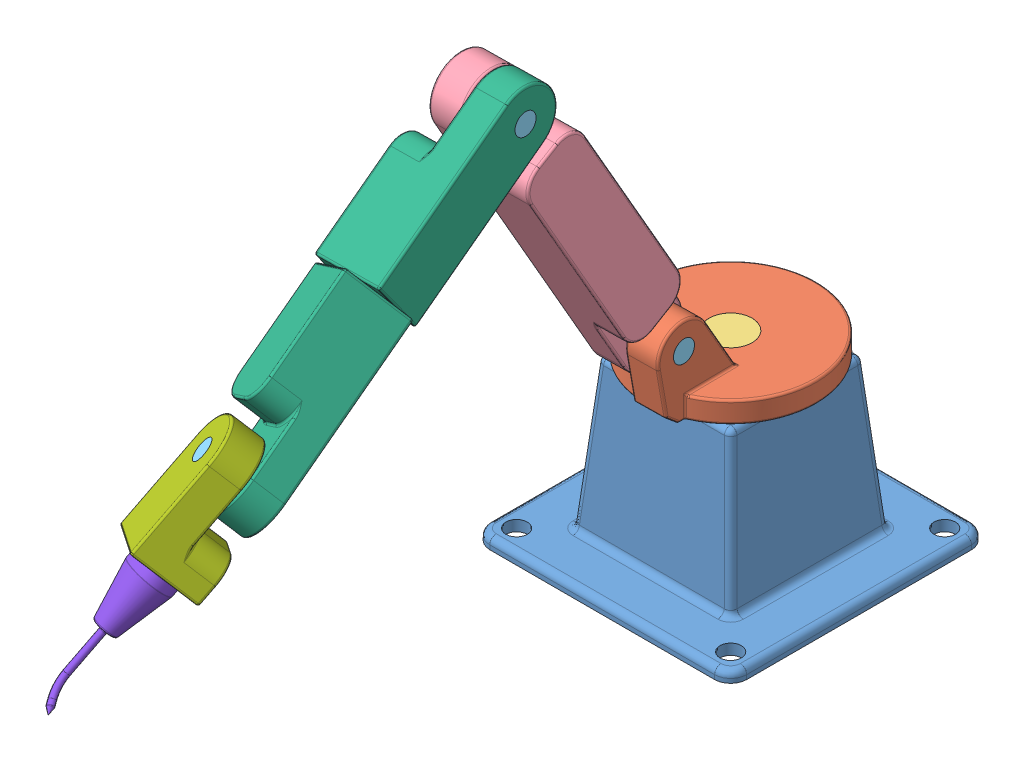
SolidWorks assembly soudeur, configuration Default. Lengths in mm.
Overall size (240 508.33 739.38).
13 component instances, 8 part files, 24 mates.
Components (placement in the parent):
- Base-1: Base [Default] at origin size (240 150 240)
- Link_T-1: Link_T [Default] at (0 150 0) x (0.013182 0 0.999913) z (-0.999913 0 0.013182) size (179.64 80.62 160)
- Pin_Long-1: Pin_Long [Default] at origin size (40 170 40)
- Link_Long-1: Link_Long [Default] at (31.9748 335.8726 149.602) x (0.006592 0.865985 0.500026) z (-0.999913 0 0.013182) size (360 61.62 60)
- Pin_Short-1: Pin_Short [Default] at (-29.0088 205.9749 75.3889) x (0.011416 0.5 0.86595) z (-0.006591 0.866025 -0.499957) size (20 60 20)
- Pin_Short-2: Pin_Short [Default] at (-27.0313 465.7704 225.3968) x (0.011416 0.5 0.86595) z (-0.006591 0.866025 -0.499957) size (20 60 20)
- Pin_Short-3: Pin_Short [Default] at (24.0899 270.1389 453.4354) x (-0.45627 -0.761977 0.459575) z (-0.659433 -0.057232 -0.749581) size (20 60 20)
- Pin_Short-4: Pin_Short [Default] at (-22.5941 210.4796 538.6491) x (0.576086 -0.652091 -0.492851) z (0.774446 0.242575 0.584287) size (20 60 20)
- Pin_Short-5: Pin_Short [Default] at (4.2461 395.2587 322.0913) x (-0.610387 0.637066 0.470717) z (0.792032 0.498874 0.351867) size (20 60 20)
- Link_Half-1: Link_Half [Default] at (-25.4314 377.6307 346.7592) x (0.010666 -0.587598 0.809083) z (0.999913 0 -0.013182) size (180 61.62 60)
- Link_Half-2: Link_Half [Default] at (-13.358 396.9828 360.6546) x (-0.010666 0.587598 -0.809083) z (0.597466 -0.64507 -0.47636) size (180 61.62 60)
- Link_End-1: Link_End [Default] at (3.1736 212.6761 505.0157) x (-0.261455 -0.718286 0.644753) z (-0.597466 0.64507 0.47636) size (110 61.62 60)
- Tool-1: Tool [Default] at (-14.7504 232.0282 519.3065) x (-0.924907 -0.004582 -0.380165) z (-0.276022 0.695733 0.66315) size (40 122.85 40)
Mates (geometry in assembly coordinates):
- Concentric1: concentric: cylinder of Base-1 through (0 150 0) axis (0 -1 0) radius 20; cylinder of Link_T-1 through (0 170 0) axis (0 -1 0) radius 20
- Coincident1: coincident: plane of Base-1 through (0 150 0) normal (0 1 0); plane of Link_T-1 through (0 150 0) normal (0 -1 0)
- Concentric2: concentric: cylinder of Link_T-1 through (0 170 0) axis (0 -1 0) radius 20; cylinder of Pin_Long-1 through (0 170 0) axis (0 -1 0) radius 20
- Coincident2: coincident: plane of Link_T-1 through (0 170 0) normal (0 1 0); plane of Pin_Long-1 through (0 170 0) normal (0 1 0)
- Concentric3: concentric: cylinder of Link_T-1 through (79.7514 205.9749 12.8343) axis (-0.514194 0 0.857674) radius 10; cylinder of Link_Long-1 through (48.8997 205.9749 64.2948) axis (0.514194 0 -0.857674) radius 10
- Coincident4: coincident: plane of Link_T-1; plane of Link_Long-1
- Concentric4: concentric: cylinder of Link_Long-1 through (48.8997 205.9749 64.2948) axis (0.514194 0 -0.857674) radius 10; cylinder of Pin_Short-1 through (79.7514 205.9749 12.8343) axis (-0.514194 0 0.857674) radius 10
- Coincident5: coincident: plane of Link_Long-1 through (187.7221 458.5647 147.5217) normal (-0.514194 0 0.857674); plane of Pin_Short-1 through (48.8997 205.9749 64.2948) normal (-0.514194 0 0.857674)
- Concentric5: concentric: cylinder of Link_Long-1 through (187.7221 458.5647 147.5217) axis (0.514194 0 -0.857674) radius 10; cylinder of Link_Half-1 through (218.5737 458.5647 96.0613) axis (-0.514194 0 0.857674) radius 10
- Coincident7: coincident: plane of Link_Long-1 through (133.7367 332.2698 80.178) normal (0.514194 0 -0.857674); plane of Link_Half-1 through (307.2463 370.425 184.2008) normal (-0.514194 0 0.857674)
- Concentric6: concentric: cylinder of Link_Long-1 through (187.7221 458.5647 147.5217) axis (0.514194 0 -0.857674) radius 10; cylinder of Pin_Short-2 through (218.5737 458.5647 96.0613) axis (-0.514194 0 0.857674) radius 10
- Coincident8: coincident: plane of Link_Long-1 through (187.7221 458.5647 147.5217) normal (-0.514194 0 0.857674); plane of Pin_Short-2 through (187.7221 458.5647 147.5217) normal (-0.514194 0 0.857674)
- Concentric7: concentric: cylinder of Pin_Short-5 through (328.066 352.7971 196.6826) axis (-0.69399 0.587598 -0.416062) radius 10; cylinder of Link_Half-1 through (286.4266 388.0529 171.7189) axis (0.69399 -0.587598 0.416062) radius 10
- Coincident9: coincident: plane of Pin_Short-5 through (286.4266 388.0529 171.7189) normal (-0.69399 0.587598 -0.416062); plane of Link_Half-1 through (286.4266 388.0529 171.7189) normal (0.69399 -0.587598 0.416062)
- Concentric8: concentric: cylinder of Pin_Short-5 through (328.066 352.7971 196.6826) axis (-0.69399 0.587598 -0.416062) radius 10; cylinder of Link_Half-2 through (328.066 352.7971 196.6826) axis (-0.69399 0.587598 -0.416062) radius 10
- Coincident11: coincident: plane of Pin_Short-5 through (328.066 352.7971 196.6826) normal (0.69399 -0.587598 0.416062); plane of Link_Half-2 through (328.066 352.7971 196.6826) normal (-0.69399 0.587598 -0.416062)
- Concentric9: concentric: cylinder of Link_Half-2 through (431.797 292.7992 227.3444) axis (-0.681741 -0.350463 0.642188) radius 10; cylinder of Link_End-1 through (390.8925 271.7714 265.8757) axis (0.681741 0.350463 -0.642188) radius 10
- Coincident13: coincident: plane of Link_Half-2; plane of Link_End-1
- Concentric10: concentric: cylinder of Pin_Short-3 through (390.8925 271.7714 265.8757) axis (0.681741 0.350463 -0.642188) radius 10; cylinder of Link_End-1 through (390.8925 271.7714 265.8757) axis (0.681741 0.350463 -0.642188) radius 10
- Coincident14: coincident: plane of Pin_Short-3 through (390.8925 271.7714 265.8757) normal (-0.681741 -0.350463 0.642188); plane of Link_End-1 through (390.8925 271.7714 265.8757) normal (-0.681741 -0.350463 0.642188)
- Concentric11: concentric: cylinder of Pin_Short-4 through (426.4013 235.5648 237.0971) axis (0.301132 -0.93441 -0.190259) radius 10; cylinder of Link_End-1 through (426.4013 235.5648 237.0971) axis (0.301132 -0.93441 -0.190259) radius 10
- Coincident16: coincident: plane of Pin_Short-4 through (426.4013 235.5648 237.0971) normal (-0.301132 0.93441 0.190259); plane of Link_End-1 through (426.4013 235.5648 237.0971) normal (0.301132 -0.93441 -0.190259)
- Concentric12: concentric: cylinder of Pin_Short-4 through (426.4013 235.5648 237.0971) axis (0.301132 -0.93441 -0.190259) radius 10; cylinder of Tool-1 through (448.0828 168.2874 223.3985) axis (0.301132 -0.93441 -0.190259) radius 10
- Coincident17: coincident: plane of Pin_Short-4 through (444.4692 179.5003 225.6816) normal (0.301132 -0.93441 -0.190259); plane of Tool-1 through (444.4692 179.5003 225.6816) normal (-0.301132 0.93441 0.190259)
